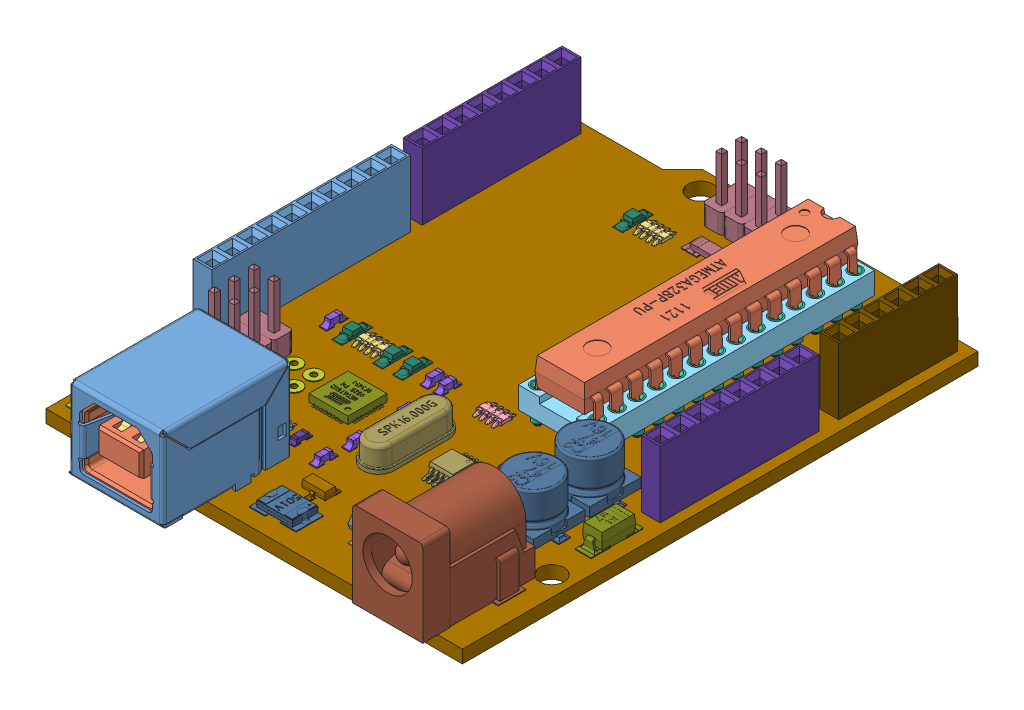
SolidWorks assembly arduino uno, configuration Default. Lengths in mm.
Overall size (53.34 15.25 74.93).
88 component instances, 35 part files, 0 mates.
Components (placement in the parent):
- USB type b-1: USB type b [Default] at (-38.02 0.43 6.35) size (13.72 15.2 16.5)
  - USB SHELL-1: USB SHELL [Default] at origin size (13.72 15.2 16.5)
  - USB core-1: USB core [Default] at origin size (11.3 10.68 15.75)
  - usb top contact-1: usb top contact [Default] at (1.25 6.09 -0.38) size (1 9.67 13.76)
  - usb top contact-2: usb top contact [Default] at (-1.25 6.09 -0.38) size (1 9.67 13.76)
  - usb btm contact-1: usb btm contact [Default] at (1.25 4.41 -0.38) size (1 6.84 11.76)
  - usb btm contact-2: usb btm contact [Default] at (-1.25 4.41 -0.38) size (1 6.84 11.76)
- dip28-1: dip28 [Default] at (-16.383 1.5 -46.355) x (0 0 -1) z (1 0 0) size (35.48 7.37 10.1)
  - dip28-1: dip28 [Default] at origin size (35.48 2.8 10.1)
  - dip socket pin-1: dip socket pin [Default] at (-6.35 2.8 -3.81) size (1.7 7.37 1.7)
  - dip socket pin-2: dip socket pin [Default] at (1.27 2.8 -3.81) size (1.7 7.37 1.7)
  - dip socket pin-3: dip socket pin [Default] at (-16.51 2.8 3.81) size (1.7 7.37 1.7)
  - dip socket pin-4: dip socket pin [Default] at (1.27 2.8 3.81) size (1.7 7.37 1.7)
  - dip socket pin-5: dip socket pin [Default] at (6.35 2.8 -3.81) size (1.7 7.37 1.7)
  - dip socket pin-6: dip socket pin [Default] at (13.97 2.8 -3.81) size (1.7 7.37 1.7)
  - dip socket pin-7: dip socket pin [Default] at (3.81 2.8 -3.81) size (1.7 7.37 1.7)
  - dip socket pin-8: dip socket pin [Default] at (-13.97 2.8 3.81) size (1.7 7.37 1.7)
  - dip socket pin-9: dip socket pin [Default] at (16.51 2.8 3.81) size (1.7 7.37 1.7)
  - dip socket pin-10: dip socket pin [Default] at (13.97 2.8 3.81) size (1.7 7.37 1.7)
  - dip socket pin-11: dip socket pin [Default] at (-1.27 2.8 3.81) size (1.7 7.37 1.7)
  - dip socket pin-12: dip socket pin [Default] at (-11.43 2.8 -3.81) size (1.7 7.37 1.7)
  - dip socket pin-13: dip socket pin [Default] at (11.43 2.8 3.81) size (1.7 7.37 1.7)
  - dip socket pin-14: dip socket pin [Default] at (-8.89 2.8 -3.81) size (1.7 7.37 1.7)
  - dip socket pin-15: dip socket pin [Default] at (-1.27 2.8 -3.81) size (1.7 7.37 1.7)
  - dip socket pin-16: dip socket pin [Default] at (16.51 2.8 -3.81) size (1.7 7.37 1.7)
  - dip socket pin-17: dip socket pin [Default] at (-13.97 2.8 -3.81) size (1.7 7.37 1.7)
  - dip socket pin-18: dip socket pin [Default] at (-3.81 2.8 3.81) size (1.7 7.37 1.7)
  - dip socket pin-19: dip socket pin [Default] at (8.89 2.8 -3.81) size (1.7 7.37 1.7)
  - dip socket pin-20: dip socket pin [Default] at (-6.35 2.8 3.81) size (1.7 7.37 1.7)
  - dip socket pin-21: dip socket pin [Default] at (3.81 2.8 3.81) size (1.7 7.37 1.7)
  - dip socket pin-22: dip socket pin [Default] at (11.43 2.8 -3.81) size (1.7 7.37 1.7)
  - dip socket pin-23: dip socket pin [Default] at (8.89 2.8 3.81) size (1.7 7.37 1.7)
  - dip socket pin-24: dip socket pin [Default] at (-16.51 2.8 -3.81) size (1.7 7.37 1.7)
  - dip socket pin-25: dip socket pin [Default] at (-3.81 2.8 -3.81) size (1.7 7.37 1.7)
  - dip socket pin-26: dip socket pin [Default] at (-8.89 2.8 3.81) size (1.7 7.37 1.7)
  - dip socket pin-27: dip socket pin [Default] at (-11.43 2.8 3.81) size (1.7 7.37 1.7)
  - dip socket pin-28: dip socket pin [Default] at (6.35 2.8 3.81) size (1.7 7.37 1.7)
- RESET BUTTON-1: RESET BUTTON [Default] at (-49.403 0 -6.35) size (6.2 3.1 9.6)
  - RESET CORE-1: RESET CORE [Default] at (0 0.1 0) x (-1 0 0) z (0 0 -1) size (6.2 3.1 9.6)
  - RESET-1: RESET [Default] at (0 0.1 0) x (0 0 1) z (-1 0 0) size (7.3 2 6.2)
- unoboard blue-1: unoboard blue [Default] at origin size (53.34 1.65 68.58)
- 47uf CAP Dcase-1: 47uf CAP Dcase [Default] at (-9.4141 0 -25.7132) x (0 0 -1) z (1 0 0) size (6.6 5.81 8)
- 47uf CAP Dcase-2: 47uf CAP Dcase [Default] at (-9.4141 0 -18.4991) x (0 0 -1) z (1 0 0) size (6.6 5.81 8)
- power jack-1: power jack [Default] at (-7.675 0 1.905) size (11.2 15.2 15.9)
- crystal-1: crystal [Default] at (-26.162 0 -18.923) x (1 0 0) z (0 0 -1) size (4 5 11)
- 2pin_header__02-1: 2pin_header__02 [Default] at (-46.23 0 -20.83) size (5 11.75 2.54)
- 2pin_header__02-2: 2pin_header__02 [Default] at (-27.89 0 -64.91) x (0 0 1) z (-1 0 0) size (5 11.75 2.54)
- 2pin_header__02-3: 2pin_header__02 [Default] at (-46.23 0 -15.75) size (5 11.75 2.54)
- 2pin_header__02-4: 2pin_header__02 [Default] at (-46.23 0 -18.29) size (5 11.75 2.54)
- 2pin_header__02-5: 2pin_header__02 [Default] at (-25.35 0 -64.91) x (0 0 1) z (-1 0 0) size (5 11.75 2.54)
- 2pin_header__02-6: 2pin_header__02 [Default] at (-30.43 0 -64.91) x (0 0 1) z (-1 0 0) size (5 11.75 2.54)
- nano - reg-1: nano - reg [Default] at (-17.399 0 -7.747) size (6.5 1.69 8.3)
- led-1: led [Default] at (-36.576 0 -58.42) x (0 0 1) z (-1 0 0) size (4 0.86 1.35)
- led-2: led [Default] at (-34.29 0 -27.94) x (0 0 1) z (-1 0 0) size (4 0.86 1.35)
- led-3: led [Default] at (-36.83 0 -27.94) x (0 0 1) z (-1 0 0) size (4 0.86 1.35)
- led-4: led [Default] at (-42.037 0 -27.94) x (0 0 1) z (-1 0 0) size (4 0.86 1.35)
- atmega16u2-1: atmega16u2 [Default] at (-34.671 0.06 -20) x (1 0 0) z (0 0 -1) size (5.5 1.01 5.5)
- 8 PORT HEADER-1: 8 PORT HEADER [Default] at (-50.8 0 -45.72) x (0 0 -1) z (1 0 0) size (20.32 10.51 2.41)
- 8 PORT HEADER-2: 8 PORT HEADER [Default] at (-2.54 0 -27.94) x (0 0 -1) z (1 0 0) size (20.32 10.51 2.41)
- 6 PORT HEADER-1: 6 PORT HEADER [Default] at (-2.54 0 -50.8) x (0 0 -1) z (1 0 0) size (15.24 10.51 2.41)
- 10 PORT HEADER-1: 10 PORT HEADER [Default] at (-50.8 0 -18.796) x (0 0 -1) z (1 0 0) size (25.4 10.51 2.41)
- ATMEL328P-1: ATMEL328P [Default] at (-16.383 4.3 -46.355) x (0 0 -1) z (1 0 0) size (35 7.27 7.87)
- 102 RESISTOR PACK-1: 102 RESISTOR PACK [Default] at (-39.37 0 -27.94) size (3.2 0.46 3)
- 102 RESISTOR PACK-2: 102 RESISTOR PACK [Default] at (-33.782 0 -58.42) size (3.2 0.46 3)
- 103 RESISTOR PACK-1: 103 RESISTOR PACK [Default] at (-23.876 0 -27.94) size (3.2 0.46 3)
- 220 RESISTOR PACK-1: 220 RESISTOR PACK [Default] at (-36.83 0 -12.827) size (3.2 0.46 3)
- 16mhz crystal - measured-1: 16mhz crystal - measured [Default] at (-24.892 0 -41.275) x (0 0 -1) z (1 0 0) size (3.4 0.8 2)
- PADS001-1: PADS001 [Default] at (-39.878 0.1 -18.288) x (-1 0 0) z (0 0 1) size (4.54 0.1 4.54)
- 603 cap on pad-1: 603 cap on pad [Default] at (-29.591 0 -22.352) x (0 0 1) z (-1 0 0) size (2.76 0.9 1.12)
- 603 cap on pad-2: 603 cap on pad [Default] at (-29.845 0 -27.94) x (0 0 -1) z (1 0 0) size (2.76 0.9 1.12)
- 603 cap on pad-3: 603 cap on pad [Default] at (-29.845 0 -12.065) x (0 0 1) z (-1 0 0) size (2.76 0.9 1.12)
- 603 cap on pad-4: 603 cap on pad [Default] at (-44.45 0 -27.94) x (0 0 -1) z (1 0 0) size (2.76 0.9 1.12)
- 603 cap on pad-5: 603 cap on pad [Default] at (-41.91 0 -12.7) x (0 0 1) z (-1 0 0) size (2.76 0.9 1.12)
- 603 cap on pad-6: 603 cap on pad [Default] at (-29.591 0 -16.002) x (0 0 1) z (-1 0 0) size (2.76 0.9 1.12)
- 603 cap on pad-7: 603 cap on pad [Default] at (-31.496 0 -27.94) x (0 0 -1) z (1 0 0) size (2.76 0.9 1.12)
- 603 cap on pad-8: 603 cap on pad [Default] at (-15.24 0 -18.415) size (2.76 0.9 1.12)
- 603 cap on pad-9: 603 cap on pad [Default] at (-15.24 0 -25.625) size (2.76 0.9 1.12)
- ssot3-1: ssot3 [Default] at (-26.5 0 -8.128) x (-1 0 0) z (0 0 -1) size (3 1.13 3.09)
- mf-msmf050-2-1: mf-msmf050-2 [Default] at (-26.5 0 -4.064) size (5.77 1.02 3.72)
- lmv358-1: lmv358 [Default] at (-15.24 0 -21.971) x (0 0 -1) z (1 0 0) size (3.7 1.4 2.9)
- lp2985dgkr-1: lp2985dgkr [Default] at (-20.32 0 -19.05) x (0 0 -1) z (1 0 0) size (5.85 1.1 3)
- cd1206 diode-1: cd1206 diode [Default] at (-27.94 0 -59.436) x (0 0 -1) z (1 0 0) size (2.07 0.96 5)
- cd1206 diode-2: cd1206 diode [Default] at (-46.228 0 -13.081) x (0 0 1) z (-1 0 0) size (2.07 0.96 5)
- 603 resistor-1: 603 resistor [Default] at (-29.591 0 -19.05) x (0 0 1) z (-1 0 0) size (2.36 0.61 1.03)
- blm21-1: blm21 [Default] at (-45.085 0 -7.62) x (0 0 -1) z (1 0 0) size (2.76 0.95 1.32)
- m7 diode-1: m7 diode [Default] at (-2.794 0 -21.59) x (0 0 -1) z (1 0 0) size (6.66 2.35 2.5)
- MLC0603-1: MLC0603 [Default] at (-33.655 0 -12.827) x (0 0 -1) z (1 0 0) size (2.36 0.6 1.03)
- MLC0603-2: MLC0603 [Default] at (-39.37 0 -12.827) x (0 0 -1) z (1 0 0) size (2.36 0.6 1.03)
